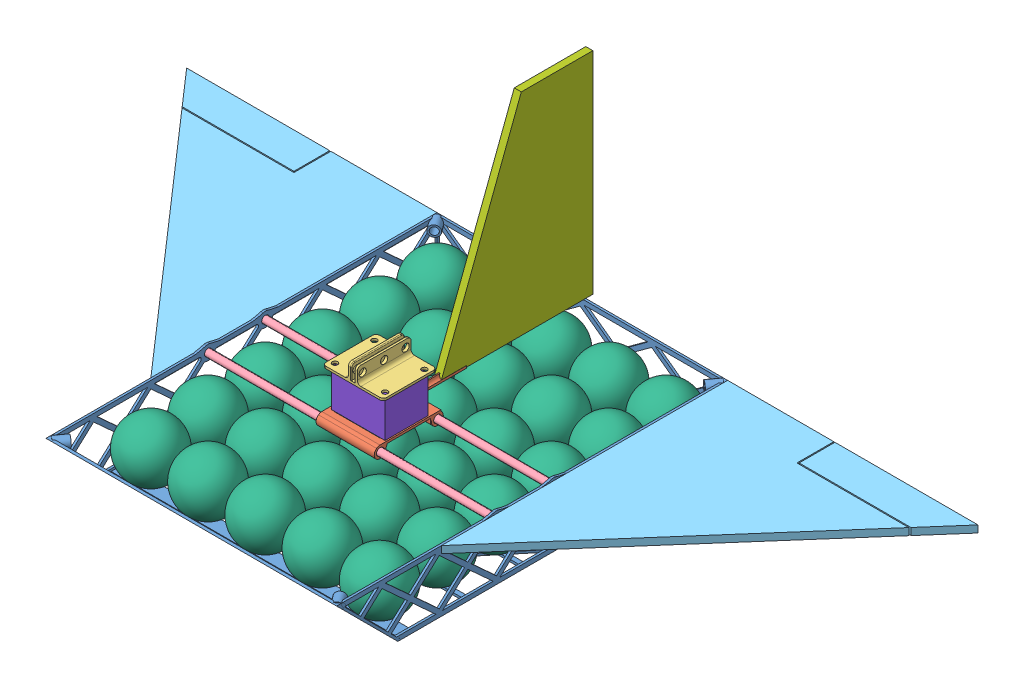
SolidWorks assembly DroneFullAssembly, configuration Default. Lengths in mm.
Overall size (561.98 223.62 297.53).
41 component instances, 8 part files, 28 mates.
Components (placement in the parent):
- DroneFrame_Ver_2-1: DroneFrame_Ver_2 [Default] at (112.4111 130.5379 218.2827) size (206.38 45.4 277.68)
- Center_Electronics_Tail_Support_Block-1: Center_Electronics_Tail_Support_Block [Default] at (112.3441 173.4854 261.4627) x (0 0 1) z (-1 0 0) size (83.59 17.95 41.57)
- DropMountAndAntennaMount-1: DropMountAndAntennaMount [Default] at (133.9341 201.373 219.5527) x (0 0 -1) z (1 0 0) size (38.1 12.13 43.18)
- 5mmCarbonRod-1: 5mmCarbonRod [Default] at (215.5986 170.8604 218.2827) x (0 0.924225 0.381849) z (-1 0 0) size (5 5 206.38)
- 5mmCarbonRod-2: 5mmCarbonRod [Default] at (215.5986 170.8604 258.9227) x (0 0 1) z (-1 0 0) size (5 5 206.38)
- Wing-1: Wing [Default] at (215.5986 169.0354 94.7752) x (-1 0 0) z (0 0 -1) size (177.8 5 203.2)
- Wing-2: Wing [Default] at (9.2236 174.0354 94.7752) x (1 0 0) z (0 0 -1) size (177.8 5 203.2)
- GliderColonistsLayout_Balls-1: GliderColonistsLayout_Balls [Default] at (96.362 -51.954 205.9731) x (0.998189 -0.00326 0.060073) z (-0.060073 -0.108113 0.992322) size (237.01 75.22 266.38)
  - PingPongBall-1: PingPongBall [Default] at (103.3294 215.1982 85.0898) x (0.318433 -0.943803 -0.088524) z (0.332607 0.023792 0.942765) size (40.64 40.64 40.64)
  - PingPongBall-146: PingPongBall [Default] at (100.888 210.8045 44.7619) x (0.318433 -0.943803 -0.088524) z (0.332607 0.023792 0.942765) size (40.64 40.64 40.64)
  - PingPongBall-147: PingPongBall [Default] at (98.4466 206.4108 4.4339) x (0.318433 -0.943803 -0.088524) z (0.332607 0.023792 0.942765) size (40.64 40.64 40.64)
  - PingPongBall-148: PingPongBall [Default] at (96.0052 202.017 -35.894) x (0.318433 -0.943803 -0.088524) z (0.332607 0.023792 0.942765) size (40.64 40.64 40.64)
  - PingPongBall-149: PingPongBall [Default] at (93.5639 197.6233 -76.222) x (0.318433 -0.943803 -0.088524) z (0.332607 0.023792 0.942765) size (40.64 40.64 40.64)
  - PingPongBall-150: PingPongBall [Default] at (91.1225 193.2296 -116.55) x (0.318433 -0.943803 -0.088524) z (0.332607 0.023792 0.942765) size (40.64 40.64 40.64)
  - PingPongBall-151: PingPongBall [Default] at (62.763 215.3307 87.5312) x (0.318433 -0.943803 -0.088524) z (0.332607 0.023792 0.942765) size (40.64 40.64 40.64)
  - PingPongBall-152: PingPongBall [Default] at (60.3216 210.937 47.2033) x (0.318433 -0.943803 -0.088524) z (0.332607 0.023792 0.942765) size (40.64 40.64 40.64)
  - PingPongBall-153: PingPongBall [Default] at (57.8802 206.5432 6.8753) x (0.318433 -0.943803 -0.088524) z (0.332607 0.023792 0.942765) size (40.64 40.64 40.64)
  - PingPongBall-154: PingPongBall [Default] at (55.4389 202.1495 -33.4527) x (0.318433 -0.943803 -0.088524) z (0.332607 0.023792 0.942765) size (40.64 40.64 40.64)
  - PingPongBall-155: PingPongBall [Default] at (52.9975 197.7558 -73.7806) x (0.318433 -0.943803 -0.088524) z (0.332607 0.023792 0.942765) size (40.64 40.64 40.64)
  - PingPongBall-156: PingPongBall [Default] at (50.5561 193.362 -114.1086) x (0.318433 -0.943803 -0.088524) z (0.332607 0.023792 0.942765) size (40.64 40.64 40.64)
  - PingPongBall-157: PingPongBall [Default] at (22.1966 215.4632 89.9726) x (0.318433 -0.943803 -0.088524) z (0.332607 0.023792 0.942765) size (40.64 40.64 40.64)
  - PingPongBall-158: PingPongBall [Default] at (19.7552 211.0694 49.6446) x (0.318433 -0.943803 -0.088524) z (0.332607 0.023792 0.942765) size (40.64 40.64 40.64)
  - PingPongBall-159: PingPongBall [Default] at (17.3138 206.6757 9.3167) x (0.318433 -0.943803 -0.088524) z (0.332607 0.023792 0.942765) size (40.64 40.64 40.64)
  - PingPongBall-160: PingPongBall [Default] at (14.8725 202.282 -31.0113) x (0.318433 -0.943803 -0.088524) z (0.332607 0.023792 0.942765) size (40.64 40.64 40.64)
  - PingPongBall-161: PingPongBall [Default] at (12.4311 197.8883 -71.3393) x (0.318433 -0.943803 -0.088524) z (0.332607 0.023792 0.942765) size (40.64 40.64 40.64)
  - PingPongBall-162: PingPongBall [Default] at (9.9897 193.4945 -111.6672) x (0.318433 -0.943803 -0.088524) z (0.332607 0.023792 0.942765) size (40.64 40.64 40.64)
  - DroneFrame_Ver_2-1: DroneFrame_Ver_2 [Default] at (16.1646 182.6999 -8.4788) x (0.998189 -0.00326 -0.060073) z (0.060073 0.108113 0.992322) size (206.38 45.4 277.68) (hidden)
  - PingPongBall-187: PingPongBall [Default] at (-18.3698 215.5957 92.414) x (0.318433 -0.943803 -0.088524) z (0.332607 0.023792 0.942765) size (40.64 40.64 40.64)
  - PingPongBall-188: PingPongBall [Default] at (-20.8112 211.2019 52.086) x (0.318433 -0.943803 -0.088524) z (0.332607 0.023792 0.942765) size (40.64 40.64 40.64)
  - PingPongBall-189: PingPongBall [Default] at (-23.2525 206.8082 11.758) x (0.318433 -0.943803 -0.088524) z (0.332607 0.023792 0.942765) size (40.64 40.64 40.64)
  - PingPongBall-190: PingPongBall [Default] at (-25.6939 202.4145 -28.5699) x (0.318433 -0.943803 -0.088524) z (0.332607 0.023792 0.942765) size (40.64 40.64 40.64)
  - PingPongBall-191: PingPongBall [Default] at (-28.1353 198.0207 -68.8979) x (0.318433 -0.943803 -0.088524) z (0.332607 0.023792 0.942765) size (40.64 40.64 40.64)
  - PingPongBall-192: PingPongBall [Default] at (-30.5767 193.627 -109.2258) x (0.318433 -0.943803 -0.088524) z (0.332607 0.023792 0.942765) size (40.64 40.64 40.64)
  - PingPongBall-193: PingPongBall [Default] at (-58.9362 215.7281 94.8553) x (0.318433 -0.943803 -0.088524) z (0.332607 0.023792 0.942765) size (40.64 40.64 40.64)
  - PingPongBall-194: PingPongBall [Default] at (-61.3775 211.3344 54.5274) x (0.318433 -0.943803 -0.088524) z (0.332607 0.023792 0.942765) size (40.64 40.64 40.64)
  - PingPongBall-195: PingPongBall [Default] at (-63.8189 206.9407 14.1994) x (0.318433 -0.943803 -0.088524) z (0.332607 0.023792 0.942765) size (40.64 40.64 40.64)
  - PingPongBall-196: PingPongBall [Default] at (-66.2603 202.5469 -26.1285) x (0.318433 -0.943803 -0.088524) z (0.332607 0.023792 0.942765) size (40.64 40.64 40.64)
  - PingPongBall-197: PingPongBall [Default] at (-68.7017 198.1532 -66.4565) x (0.318433 -0.943803 -0.088524) z (0.332607 0.023792 0.942765) size (40.64 40.64 40.64)
  - PingPongBall-198: PingPongBall [Default] at (-71.1431 193.7595 -106.7845) x (0.318433 -0.943803 -0.088524) z (0.332607 0.023792 0.942765) size (40.64 40.64 40.64)
- Vertical_Tail-1: Vertical_Tail [Default] at (112.3041 174.0354 89.6952) size (5 149.86 107.95)
- FILLER BLOCK-1: FILLER BLOCK [Default] at (132.0291 175.084 254.4777) size (38.1 26.29 30.48)
Mates (geometry in assembly coordinates):
- Concentric1: concentric aligned: cylinder of DroneFrame_Ver_2-1 through (10.8111 170.8604 258.9227) axis (-1 0 0) radius 2.6; cylinder of Center_Electronics_Tail_Support_Block-1 through (132.9816 170.8604 258.9227) axis (-1 0 0) radius 2.625
- Concentric2: concentric aligned: cylinder of DroneFrame_Ver_2-1 through (10.8111 170.8604 218.2827) axis (-1 0 0) radius 2.6; cylinder of Center_Electronics_Tail_Support_Block-1 through (132.9816 170.8604 218.2827) axis (-1 0 0) radius 2.625
- Parallel1: parallel aligned: plane of DroneFrame_Ver_2-1 through (112.4111 174.0354 218.2827) normal (0 1 0); plane of Center_Electronics_Tail_Support_Block-1 through (112.3441 175.0729 261.4627) normal (0 1 0)
- Concentric3: concentric anti-aligned: cylinder of Center_Electronics_Tail_Support_Block-1 through (130.1241 143.9579 252.5727) axis (0 1 0) radius 1.905; cylinder of DropMountAndAntennaMount-1 through (130.1241 202.9605 252.5727) axis (0 -1 0) radius 1.905
- Concentric4: concentric anti-aligned: cylinder of Center_Electronics_Tail_Support_Block-1 through (94.5641 143.9579 224.6327) axis (0 1 0) radius 1.905; cylinder of DropMountAndAntennaMount-1 through (94.5641 202.9605 224.6327) axis (0 -1 0) radius 1.905
- Concentric5: concentric anti-aligned: cylinder of DroneFrame_Ver_2-1 through (10.8111 170.8604 258.9227) axis (-1 0 0) radius 2.6; cylinder of 5mmCarbonRod-2 through (9.2236 170.8604 258.9227) axis (1 0 0) radius 2
- Coincident2: coincident aligned: plane of DroneFrame_Ver_2-1 through (9.2236 132.1254 218.2827) normal (-1 0 0); plane of 5mmCarbonRod-2 through (9.2236 170.8604 258.9227) normal (-1 0 0)
- Coincident3: coincident aligned: plane of DroneFrame_Ver_2-1 through (9.2236 132.1254 218.2827) normal (-1 0 0); plane of 5mmCarbonRod-1 through (9.2236 170.8604 218.2827) normal (-1 0 0)
- Concentric6: concentric aligned: cylinder of DroneFrame_Ver_2-1 through (10.8111 170.8604 218.2827) axis (-1 0 0) radius 2.6; circle of 5mmCarbonRod-1
- Coincident9: coincident aligned: plane of DroneFrame_Ver_2-1 through (112.4111 132.1254 94.7752) normal (0 0 -1); plane of Wing-2 through (9.2236 169.0354 94.7752) normal (0 0 -1)
- Coincident10: coincident aligned: plane of DroneFrame_Ver_2-1 through (112.4111 174.0354 218.2827) normal (0 1 0); plane of Wing-2 through (9.2236 174.0354 94.7752) normal (0 1 0)
- Coincident11: coincident anti-aligned: plane of DroneFrame_Ver_2-1 through (9.2236 132.1254 218.2827) normal (-1 0 0); plane of Wing-2 through (9.2236 169.0354 94.7752) normal (1 0 0)
- Coincident12: coincident anti-aligned: plane of DroneFrame_Ver_2-1 through (215.5986 132.1254 218.2827) normal (1 0 0); plane of Wing-1 through (215.5986 174.0354 94.7752) normal (-1 0 0)
- Coincident13: coincident aligned: plane of DroneFrame_Ver_2-1 through (112.4111 174.0354 218.2827) normal (0 1 0); plane of Wing-1 through (215.5986 174.0354 94.7752) normal (0 1 0)
- Coincident14: coincident aligned: plane of DroneFrame_Ver_2-1 through (112.4111 132.1254 94.7752) normal (0 0 -1); plane of Wing-1 through (215.5986 174.0354 94.7752) normal (0 0 -1)
- Tangent1: tangent anti-aligned: plane of DroneFrame_Ver_2-1 through (112.4111 132.1254 218.2827) normal (0 1 0); sphere of GliderColonistsLayout_Balls-1/PingPongBall-1
- Tangent5: tangent anti-aligned: plane of DroneFrame_Ver_2-1 through (112.4111 132.1254 96.3627) normal (0 0 1); sphere of GliderColonistsLayout_Balls-1/PingPongBall-150
- Tangent6: tangent anti-aligned: plane of DroneFrame_Ver_2-1 through (214.0111 132.1254 218.2827) normal (-1 0 0); sphere of GliderColonistsLayout_Balls-1/PingPongBall-150
- Tangent7: tangent anti-aligned: plane of DroneFrame_Ver_2-1 through (112.4111 132.1254 218.2827) normal (0 1 0); sphere of GliderColonistsLayout_Balls-1/PingPongBall-150
- Tangent8: tangent anti-aligned: plane of DroneFrame_Ver_2-1 through (112.4111 132.1254 96.3627) normal (0 0 1); sphere of GliderColonistsLayout_Balls-1/PingPongBall-198
- Tangent9: tangent anti-aligned: plane of DroneFrame_Ver_2-1 through (112.4111 132.1254 218.2827) normal (0 1 0); sphere of GliderColonistsLayout_Balls-1/PingPongBall-198
- Parallel2: parallel aligned: plane of Center_Electronics_Tail_Support_Block-1 through (112.3441 173.4854 261.4627) normal (0 -1 0); plane of Vertical_Tail-1 through (114.8041 174.0354 89.6952) normal (0 -1 0)
- Coincident16: coincident aligned: plane of Center_Electronics_Tail_Support_Block-1 through (109.8041 175.0729 215.7427) normal (-1 0 0); plane of Vertical_Tail-1 through (109.8041 174.0354 89.6952) normal (-1 0 0)
- Coincident17: coincident anti-aligned: plane of DroneFrame_Ver_2-1 through (112.4111 174.0354 218.2827) normal (0 1 0); plane of Vertical_Tail-1 through (114.8041 174.0354 89.6952) normal (0 -1 0)
- Distance1: distance = 5.08 mm aligned: plane of Vertical_Tail-1 through (114.8041 323.8954 89.6952) normal (0 0 -1); plane of DroneFrame_Ver_2-1 through (112.4111 132.1254 94.7752) normal (0 0 -1)
- Tangent10: tangent aligned: cylinder of DropMountAndAntennaMount-1 through (94.5641 202.9605 252.5727) axis (0 -1 0) radius 1.905; plane of FILLER BLOCK-1 through (132.0291 188.8435 254.4777) normal (0 0 1)
- Tangent11: tangent aligned: cylinder of DropMountAndAntennaMount-1 through (130.1241 202.9605 224.6327) axis (0 -1 0) radius 1.905; plane of FILLER BLOCK-1 through (132.0291 188.8435 254.4777) normal (1 0 0)
- Coincident19: coincident anti-aligned: plane of DropMountAndAntennaMount-1 through (133.9341 201.373 219.5527) normal (0 -1 0); plane of FILLER BLOCK-1 through (132.0291 201.373 254.4777) normal (0 1 0)
